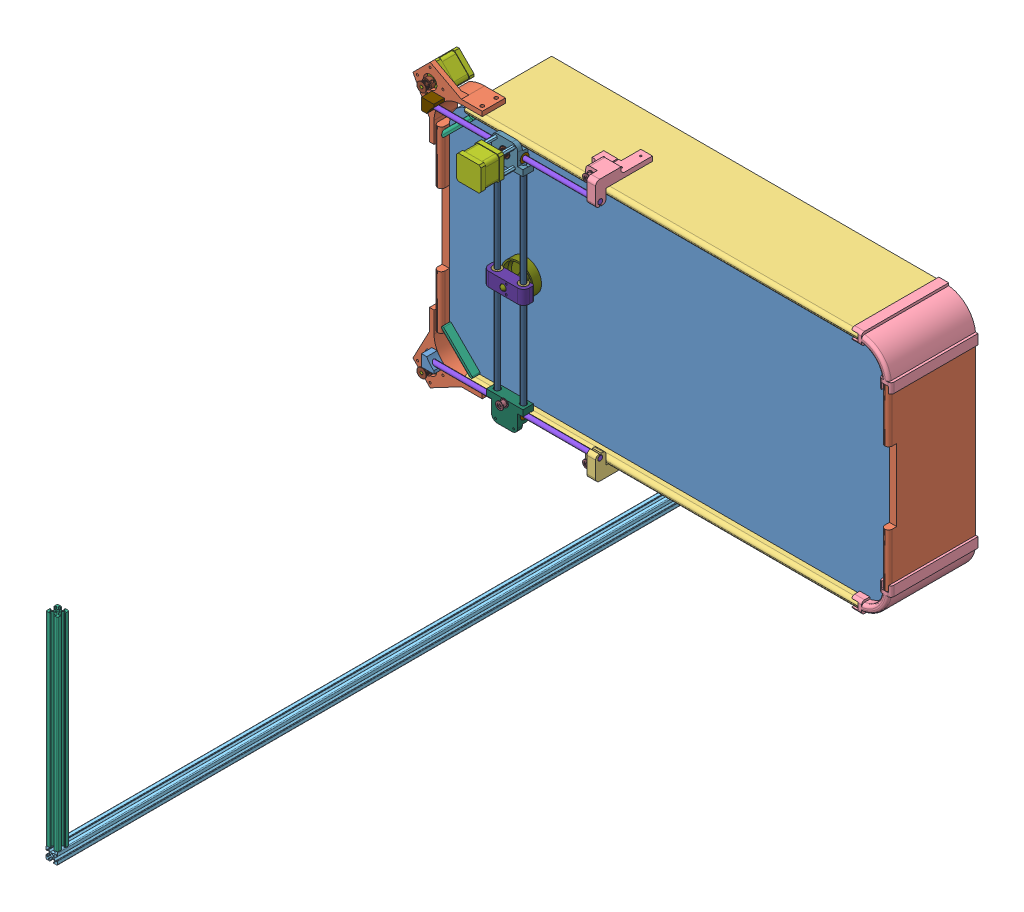
SolidWorks assembly 装配体, configuration 默认. Lengths in mm.
Overall size (823.44 485.88 1200).
44 component instances, 24 part files, 78 mates.
Components (placement in the parent):
- 球桌装配体-1: 球桌装配体 [默认] at (-24.8276 -49.5727 84.8566) size (787 421 150.29)
  - 桌面-1: 桌面 [默认] at (-446.8108 -166.0429 753) size (758 388 10)
  - 前后侧边-1: 前后侧边 [默认] at (-459.3108 -126.0429 627) x (0 1 0) z (1 0 0) size (308 150 12.5)
  - 左右侧边-1: 左右侧边 [默认] at (-406.8108 -166.0429 627) x (1 0 0) z (0 -1 0) size (678 150 12.5)
  - 左右侧边-2: 左右侧边 [默认] at (271.1892 221.9571 627) x (-1 0 0) z (0 1 0) size (678 150 12.5)
  - 前后侧边-2: 前后侧边 [默认] at (311.1892 -126.0429 627) x (0 1 0) z (1 0 0) size (308 150 12.5)
  - 倒角-1: 倒角 [默认] at (271.1892 -126.0429 777) x (1 0 0) z (0 0 -1) size (67.5 67.5 150.29)
  - 倒角-2: 倒角 [默认] at (271.1892 181.9571 777) x (0 1 0) z (0 0 -1) size (67.5 67.5 150.29)
- 摄像头支架装配体-1: 摄像头支架装配体 [默认] at (-93.6742 -242.7465 2511.8566) x (0 -1 0) z (0 0 -1) size (370 20 1200)
  - 2020型材-1: 2020型材 [默认<按加工>] at (-14.6309 -11.0359 600) size (20 20 1200)
  - 2020型材-2-1: 2020型材-2 [默认<按加工>] at (-364.6309 -11.0359 620) x (0 0 -1) z (1 0 0) size (20 20 350)
- 42步进-1: 42步进 [默认] at (-490.8785 191.6245 813.8566) x (-0.707107 -0.707107 0) z (0 0 1) size (42 42 63)
- 42步进-2: 42步进 [默认] at (-490.8785 -234.8557 813.8566) x (-0.707107 -0.707107 0) z (0 0 1) size (42 42 63)
- 300mm光轴-1: 300mm光轴 [默认] at (-487.8785 169.7044 871.8566) x (0 0.289314 0.957234) z (1 0 0) size (8 8 300)
- LM8UU直线轴承-45mm-1: LM8UU直线轴承-45mm [默认] at (-318.1095 169.7044 871.8566) x (0 0.333036 -0.942914) z (-1 0 0) size (15 15 45)
- 300mm光轴-2: 300mm光轴 [默认] at (-487.8785 -212.9356 871.8566) x (0 -0.484827 -0.87461) z (1 0 0) size (8 8 300)
- LM8UU直线轴承-45mm-2: LM8UU直线轴承-45mm [默认] at (-318.1095 -212.9356 871.8566) x (0 -0.829407 0.558645) z (-1 0 0) size (15 15 45)
- 450mm光轴-1: 450mm光轴 [默认] at (-363.1095 -199.2956 873.8566) x (-0.123162 0 0.992387) z (0 1 0) size (8 8 362)
- 450mm光轴-2: 450mm光轴 [默认] at (-318.1095 -199.2956 873.8566) x (-0.998234 0 0.059405) z (0 1 0) size (8 8 362)
- GT2同步轮内孔5-1: GT2同步轮内孔5 [默认] at (-490.8785 191.6245 860.8566) x (0.74409 0.66808 0) z (0 0 1) size (16 16 16)
- LM8UU直线轴承-24mm-1: LM8UU直线轴承-24mm [默认] at (-318.1095 -15.6742 873.8566) x (1 0 0) z (0 -1 0) size (15 15 24)
- LM8UU直线轴承-24mm-2: LM8UU直线轴承-24mm [默认] at (-363.1095 -15.6742 873.8566) x (1 0 0) z (0 -1 0) size (15 15 24)
- 惰轮（小）-1: 惰轮（小） [默认] at (-212.9285 191.6644 862.8566) size (13 13 9)
- Y轴滑块-左-1: Y轴滑块-左 [默认] at (-372.1095 182.2044 865.8566) x (1 0 0) z (0 -1 0) size (63 18 42)
- GT2同步轮内孔5-2: GT2同步轮内孔5 [默认] at (-490.8785 -234.8557 860.8566) x (0.265927 0.963993 0) z (0 0 1) size (16 16 16)
- Y轴滑块-右-1: Y轴滑块-右 [默认] at (-309.1095 -225.4356 865.8566) x (-1 0 0) z (0 1 0) size (63 18 42)
- 42步进-3: 42步进 [默认] at (-340.6095 172.9544 945.8566) x (0 1 0) z (0 0 -1) size (42 42 63)
- GT2同步轮内孔5-3: GT2同步轮内孔5 [默认] at (-340.6095 172.9544 898.8566) x (-0.6149 0.788605 0) z (0 0 -1) size (16 16 16)
- 惰轮（小）-2: 惰轮（小） [默认] at (-340.6095 -200.6856 884.8566) size (13 13 9)
- 打击器-2: 打击器 [默认] at (-340.6095 -27.6742 847.8566) x (0.889569 -0.456801 0) z (0 0 1) size (55 55 42)
- X轴滑块-3: X轴滑块 [默认] at (-375.6095 -39.6742 886.3566) x (1 0 0) z (0 1 0) size (70 19 24)
- 惰轮（小）-3: 惰轮（小） [默认] at (-212.9285 -234.8956 862.8566) x (0.977583 -0.210549 0) z (0 0 1) size (13 13 9)
- Y轴下端-1: Y轴下端 [默认] at (-487.8785 179.7044 861.8566) x (0 -1 0) z (0 0 1) size (20 29.29 18)
- Y轴下端-右-1: Y轴下端-右 [默认] at (-487.8785 -222.9356 879.8566) x (0 1 0) z (0 0 -1) size (20 29.29 18)
- 步进电机固定架-2: 步进电机固定架 [默认] at (-484.1384 184.8844 861.8566) x (1 0 0) z (0 0 -1) size (119.44 119.44 40)
- 步进电机固定架-3: 步进电机固定架 [默认] at (-484.1384 -228.1156 861.8566) x (0 1 0) z (0 0 -1) size (119.44 119.44 40)
- Y轴顶端固定件-右-2: Y轴顶端固定件-右 [默认] at (-202.8785 -236.1156 835.8566) x (0 1 0) z (1 0 0) size (40.92 98 50)
- Y轴顶端固定件-左-1: Y轴顶端固定件-左 [默认] at (-187.8785 192.8844 781.8566) x (0 -1 0) z (-1 0 0) size (40.92 98 50)
- 铜柱-1: 铜柱 [默认] at (-325.1095 188.4544 883.8566) size (6.35 5.5 27)
- 铜柱-2: 铜柱 [默认] at (-356.1095 188.4544 883.8566) x (0.90663 -0.421927 0) z (0 0 1) size (6.35 5.5 27)
- 铜柱-3: 铜柱 [默认] at (-325.1095 157.4544 883.8566) size (6.35 5.5 27)
- 铜柱-4: 铜柱 [默认] at (-356.1095 157.4544 883.8566) size (6.35 5.5 27)
- 机器人侧角件-1: 机器人侧角件 [默认] at (-471.6384 116.4902 847.8566) x (-1 0 0) z (0 0 1) size (53.07 53.07 13.51)
- 机器人侧角件-2: 机器人侧角件 [默认] at (-415.7442 -215.6156 847.8566) x (0 -1 0) z (0 0 1) size (53.07 53.07 13.51)
Mates (geometry in assembly coordinates):
- 重合2: coincident anti-aligned: plane of 球桌装配体-1/左右侧边-1 through (-431.6384 -228.1156 711.8566) normal (0 -1 0); plane of 摄像头支架装配体-1/2020型材-1 through (-82.6384 -228.1156 711.8566) normal (0 1 0)
- 重合3: coincident aligned: plane of 球桌装配体-1/左右侧边-1 through (-431.6384 -228.1156 711.8566) normal (0 0 -1); plane of 摄像头支架装配体-1/2020型材-1 through (-82.6384 -228.1156 711.8566) normal (0 0 -1)
- 距离1: distance = 381.5 mm aligned: plane of 摄像头支架装配体-1/2020型材-1 through (-82.6384 -228.1156 711.8566) normal (1 0 0); plane of 球桌装配体-1/前后侧边-2 through (298.8616 -175.6156 711.8566) normal (1 0 0)
- 同心6: concentric anti-aligned: cylinder of 300mm光轴-1 through (-187.8785 169.7044 871.8566) axis (-1 0 0) radius 4; cylinder of LM8UU直线轴承-45mm-1 through (-363.1095 169.7044 871.8566) axis (1 0 0) radius 4
- 同心11: concentric anti-aligned: cylinder of 300mm光轴-2 through (-187.8785 -212.9356 871.8566) axis (-1 0 0) radius 4; cylinder of LM8UU直线轴承-45mm-2 through (-363.1095 -212.9356 871.8566) axis (1 0 0) radius 4
- 同心19: concentric anti-aligned: cylinder of 42步进-1 through (-490.8785 191.6245 876.8566) axis (0 0 -1) radius 2.5; cylinder of GT2同步轮内孔5-1 through (-490.8785 191.6245 855.8566) axis (0 0 1) radius 2.5
- 重合28: coincident aligned: plane of 42步进-1 through (-490.8764 195.2003 876.8566) normal (0 0 1); plane of GT2同步轮内孔5-1 through (-490.8785 191.6245 876.8566) normal (0 0 1)
- 同心28: concentric anti-aligned: cylinder of 450mm光轴-2 through (-318.1095 162.7044 873.8566) axis (0 -1 0) radius 4; cylinder of LM8UU直线轴承-24mm-1 through (-318.1095 -39.6742 873.8566) axis (0 1 0) radius 4
- 同心29: concentric anti-aligned: cylinder of 450mm光轴-1 through (-363.1095 162.7044 873.8566) axis (0 -1 0) radius 4; cylinder of LM8UU直线轴承-24mm-2 through (-363.1095 -39.6742 873.8566) axis (0 1 0) radius 4
- 重合32: coincident aligned: plane of LM8UU直线轴承-24mm-1 through (-318.1095 -15.6742 873.8566) normal (0 1 0); plane of LM8UU直线轴承-24mm-2 through (-363.1095 -15.6742 873.8566) normal (0 1 0)
- 同心36: concentric anti-aligned: cylinder of LM8UU直线轴承-45mm-1 through (-363.1095 169.7044 871.8566) axis (1 0 0) radius 7.5; cylinder of Y轴滑块-左-1 through (-303.1095 169.7044 871.8566) axis (-1 0 0) radius 7.65
- 同心38: concentric aligned: cylinder of 450mm光轴-2 through (-318.1095 162.7044 873.8566) axis (0 -1 0) radius 4; cylinder of Y轴滑块-左-1 through (-318.1095 168.2044 873.8566) axis (0 -1 0) radius 4.2
- 重合37: coincident aligned: plane of LM8UU直线轴承-45mm-1 through (-363.1095 169.7044 871.8566) normal (-1 0 0); plane of Y轴滑块-左-1 through (-363.1095 162.7044 848.8566) normal (-1 0 0)
- 重合38: coincident aligned: plane of 42步进-2 through (-490.8764 -231.2799 876.8566) normal (0 0 1); plane of GT2同步轮内孔5-2 through (-490.8785 -234.8557 876.8566) normal (0 0 1)
- 同心39: concentric anti-aligned: cylinder of 42步进-2 through (-490.8785 -234.8557 876.8566) axis (0 0 -1) radius 2.5; cylinder of GT2同步轮内孔5-2 through (-490.8785 -234.8557 855.8566) axis (0 0 1) radius 2.5
- 同心40: concentric aligned: cylinder of LM8UU直线轴承-45mm-2 through (-363.1095 -212.9356 871.8566) axis (1 0 0) radius 7.5; cylinder of Y轴滑块-右-1 through (-378.1095 -212.9356 871.8566) axis (1 0 0) radius 7.65
- 同心42: concentric anti-aligned: cylinder of 450mm光轴-1 through (-363.1095 162.7044 873.8566) axis (0 -1 0) radius 4; cylinder of Y轴滑块-右-1 through (-363.1095 -211.4356 873.8566) axis (0 1 0) radius 4.2
- 同心43: concentric aligned: cylinder of 450mm光轴-1 through (-363.1095 162.7044 873.8566) axis (0 -1 0) radius 4; cylinder of Y轴滑块-左-1 through (-363.1095 168.2044 873.8566) axis (0 -1 0) radius 4.2
- 同心46: concentric aligned: cylinder of Y轴滑块-左-1 through (-340.6095 172.9544 875.8566) axis (0 0 1) radius 9; cylinder of 42步进-3 through (-340.6095 172.9544 903.8566) axis (0 0 1) radius 11
- 平行4: parallel aligned: plane of Y轴滑块-左-1 through (-372.1095 194.2044 865.8566) normal (0 1 0); plane of 42步进-3 through (-322.6095 193.9544 913.8566) normal (0 1 0)
- 重合40: coincident aligned: plane of 42步进-3 through (-343.1365 170.4244 882.8566) normal (0 0 -1); plane of GT2同步轮内孔5-3 through (-340.6095 172.9544 882.8566) normal (0 0 -1)
- 同心47: concentric anti-aligned: cylinder of 42步进-3 through (-340.6095 172.9544 882.8566) axis (0 0 1) radius 2.5; cylinder of GT2同步轮内孔5-3 through (-340.6095 172.9544 903.8566) axis (0 0 -1) radius 2.5
- 重合41: coincident aligned: plane of Y轴滑块-左-1 through (-372.1095 152.2044 883.8566) normal (0 0 1); plane of GT2同步轮内孔5-3 through (-340.6095 172.9544 883.8566) normal (0 0 1)
- 重合42: coincident anti-aligned: plane of Y轴滑块-右-1 through (-309.1095 -195.4356 883.8566) normal (0 0 1); plane of 惰轮（小）-2 through (-340.6095 -200.6856 883.8566) normal (0 0 -1)
- 同心48: concentric anti-aligned: cylinder of Y轴滑块-右-1 through (-340.6095 -200.6856 863.8566) axis (0 0 1) radius 1.65; cylinder of 惰轮（小）-2 through (-340.6095 -200.6856 895.8566) axis (0 0 -1) radius 1.5
- 重合43: coincident anti-aligned: plane of 球桌装配体-1/桌面-1 through (-471.6384 -215.6156 847.8566) normal (0 0 1); plane of 打击器-2 through (-340.6095 -27.6742 847.8566) normal (0 0 -1)
- 同心50: concentric aligned: cylinder of LM8UU直线轴承-24mm-1 through (-318.1095 -39.6742 873.8566) axis (0 1 0) radius 7.5; cylinder of X轴滑块-3 through (-318.1095 -39.6742 873.8566) axis (0 1 0) radius 7.65
- 同心51: concentric aligned: cylinder of LM8UU直线轴承-24mm-2 through (-363.1095 -39.6742 873.8566) axis (0 1 0) radius 7.5; cylinder of X轴滑块-3 through (-363.1095 -39.6742 873.8566) axis (0 1 0) radius 7.65
- 重合44: coincident aligned: plane of LM8UU直线轴承-24mm-2 through (-363.1095 -39.6742 873.8566) normal (0 -1 0); plane of X轴滑块-3 through (-375.6095 -39.6742 886.3566) normal (0 -1 0)
- 同心52: concentric anti-aligned: cylinder of 打击器-2 through (-340.6095 -27.6742 889.8566) axis (0 0 -1) radius 5; cylinder of X轴滑块-3 through (-340.6095 -27.6742 862.3566) axis (0 0 1) radius 5.3
- 重合45: coincident aligned: plane of LM8UU直线轴承-45mm-2 through (-363.1095 -212.9356 871.8566) normal (-1 0 0); plane of Y轴滑块-右-1 through (-363.1095 -225.4356 848.8566) normal (-1 0 0)
- 同心57: concentric aligned: cylinder of 300mm光轴-1 through (-187.8785 169.7044 871.8566) axis (-1 0 0) radius 4; cylinder of Y轴下端-1 through (-459.8785 169.7044 871.8566) axis (-1 0 0) radius 4.2
- 同心60: concentric aligned: cylinder of 300mm光轴-2 through (-187.8785 -212.9356 871.8566) axis (-1 0 0) radius 4; cylinder of Y轴下端-右-1 through (-459.8785 -212.9356 871.8566) axis (-1 0 0) radius 4.2
- 重合68: coincident aligned: plane of 300mm光轴-1 through (-487.8785 169.7044 871.8566) normal (-1 0 0); plane of Y轴下端-1 through (-487.8785 179.7044 879.8566) normal (-1 0 0)
- 重合69: coincident aligned: plane of 300mm光轴-2 through (-487.8785 -212.9356 871.8566) normal (-1 0 0); plane of Y轴下端-右-1 through (-487.8785 -222.9356 861.8566) normal (-1 0 0)
- 重合70: coincident aligned: plane of 球桌装配体-1/倒角-2 through (246.3616 132.3844 861.8566) normal (0 0 1); plane of 步进电机固定架-2 through (-437.1384 137.8844 861.8566) normal (0 0 1)
- 重合71: coincident anti-aligned: plane of 球桌装配体-1/左右侧边-2 through (246.3616 184.8844 711.8566) normal (0 1 0); plane of 步进电机固定架-2 through (-437.1384 184.8844 821.8566) normal (0 -1 0)
- 重合72: coincident anti-aligned: plane of 球桌装配体-1/前后侧边-1 through (-484.1384 -175.6156 711.8566) normal (-1 0 0); plane of 步进电机固定架-2 through (-484.1384 137.8844 821.8566) normal (1 0 0)
- 重合73: coincident anti-aligned: plane of 42步进-1 through (-490.8785 221.323 853.8566) normal (0 0 1); plane of 步进电机固定架-2 through (-437.1384 137.8844 853.8566) normal (0 0 -1)
- 同心61: concentric anti-aligned: cylinder of 42步进-1 through (-490.8785 191.6245 855.8566) axis (0 0 -1) radius 11; cylinder of 步进电机固定架-2 through (-490.8785 191.6245 853.8566) axis (0 0 1) radius 11.5
- 平行5: parallel aligned: plane of 42步进-1 through (-492.9998 219.2017 845.8566) normal (-0.707107 0.707107 0); plane of 步进电机固定架-2 through (-490.8785 221.323 853.8566) normal (-0.707107 0.707107 0)
- 重合74: coincident anti-aligned: plane of Y轴下端-1 through (-437.1385 137.8844 861.8566) normal (0 0 -1); plane of 步进电机固定架-2 through (-437.1384 137.8844 861.8566) normal (0 0 1)
- 同心62: concentric aligned: cylinder of Y轴下端-1 through (-490.8785 169.7044 856.8566) axis (0 0 1) radius 1.6; cylinder of 步进电机固定架-2 through (-490.8785 169.7042 853.8566) axis (0 0 1) radius 1.8
- 重合79: coincident aligned: plane of 步进电机固定架-2 through (-437.1384 137.8844 861.8566) normal (0 0 1); plane of 步进电机固定架-3 through (-437.1384 -181.1156 861.8566) normal (0 0 1)
- 重合80: coincident anti-aligned: plane of 球桌装配体-1/左右侧边-1 through (-431.6384 -228.1156 711.8566) normal (0 -1 0); plane of 步进电机固定架-3 through (-437.1384 -228.1156 821.8566) normal (0 1 0)
- 重合81: coincident anti-aligned: plane of 球桌装配体-1/前后侧边-1 through (-484.1384 -175.6156 711.8566) normal (-1 0 0); plane of 步进电机固定架-3 through (-484.1384 -181.1156 821.8566) normal (1 0 0)
- 重合82: coincident anti-aligned: plane of 42步进-2 through (-490.8785 -205.1573 853.8566) normal (0 0 1); plane of 步进电机固定架-3 through (-437.1384 -181.1156 853.8566) normal (0 0 -1)
- 同心65: concentric anti-aligned: cylinder of 42步进-2 through (-490.8785 -234.8557 855.8566) axis (0 0 -1) radius 11; cylinder of 步进电机固定架-3 through (-490.8785 -234.8557 853.8566) axis (0 0 1) radius 11.5
- 平行8: parallel aligned: plane of 42步进-2 through (-492.9998 -262.4329 845.8566) normal (-0.707107 -0.707107 0); plane of 步进电机固定架-3 through (-520.577 -234.8557 853.8566) normal (-0.707107 -0.707107 0)
- 同心66: concentric anti-aligned: cylinder of 450mm光轴-2 through (-318.1095 162.7044 873.8566) axis (0 -1 0) radius 4; cylinder of Y轴滑块-右-1 through (-318.1095 -211.4356 873.8566) axis (0 1 0) radius 4.2
- 重合84: coincident anti-aligned: plane of Y轴下端-右-1 through (-437.1385 -181.1156 861.8566) normal (0 0 -1); plane of 步进电机固定架-3 through (-437.1384 -181.1156 861.8566) normal (0 0 1)
- 同心67: concentric aligned: cylinder of Y轴下端-右-1 through (-490.8785 -212.9356 856.8566) axis (0 0 1) radius 1.6; cylinder of 步进电机固定架-3 through (-490.8785 -212.9354 853.8566) axis (0 0 1) radius 1.8
- 同心68: concentric aligned: cylinder of 300mm光轴-2 through (-187.8785 -212.9356 871.8566) axis (-1 0 0) radius 4; cylinder of Y轴顶端固定件-右-2 through (-187.8785 -212.9356 871.8566) axis (-1 0 0) radius 4.2
- 重合85: coincident anti-aligned: plane of 球桌装配体-1/左右侧边-1 through (-431.6384 -228.1156 711.8566) normal (0 -1 0); plane of Y轴顶端固定件-右-2 through (-187.8785 -228.1156 781.8566) normal (0 1 0)
- 重合86: coincident aligned: plane of 300mm光轴-2 through (-187.8785 -212.9356 871.8566) normal (1 0 0); plane of Y轴顶端固定件-右-2 through (-187.8785 -236.1156 835.8566) normal (1 0 0)
- 重合87: coincident anti-aligned: plane of 惰轮（小）-3 through (-212.9285 -234.8956 861.8566) normal (0 0 -1); plane of Y轴顶端固定件-右-2 through (-222.8785 -228.1156 861.8566) normal (0 0 1)
- 同心69: concentric anti-aligned: cylinder of 惰轮（小）-3 through (-212.9285 -234.8956 873.8566) axis (0 0 -1) radius 1.5; cylinder of Y轴顶端固定件-右-2 through (-212.9285 -234.8956 768.8566) axis (0 0 1) radius 1.6
- 同心70: concentric aligned: cylinder of 300mm光轴-1 through (-187.8785 169.7044 871.8566) axis (-1 0 0) radius 4; cylinder of Y轴顶端固定件-左-1 through (-172.8785 169.7044 871.8566) axis (-1 0 0) radius 4.2
- 重合88: coincident anti-aligned: plane of 球桌装配体-1/左右侧边-2 through (246.3616 184.8844 711.8566) normal (0 1 0); plane of Y轴顶端固定件-左-1 through (-202.8785 184.8844 781.8566) normal (0 -1 0)
- 重合89: coincident aligned: plane of 300mm光轴-1 through (-187.8785 169.7044 871.8566) normal (1 0 0); plane of Y轴顶端固定件-左-1 through (-187.8785 192.8844 781.8566) normal (1 0 0)
- 重合90: coincident anti-aligned: plane of 惰轮（小）-1 through (-212.9285 191.6644 861.8566) normal (0 0 -1); plane of Y轴顶端固定件-左-1 through (-222.8785 184.8844 861.8566) normal (0 0 1)
- 同心71: concentric anti-aligned: cylinder of 惰轮（小）-1 through (-212.9285 191.6644 873.8566) axis (0 0 -1) radius 1.5; cylinder of Y轴顶端固定件-左-1 through (-212.9285 191.6644 682.8566) axis (0 0 1) radius 1.6
- 重合95: coincident aligned: plane of 450mm光轴-2 through (-318.1095 162.7044 873.8566) normal (0 1 0); plane of Y轴滑块-左-1 through (-318.1095 162.7044 848.8566) normal (0 1 0)
- 重合96: coincident aligned: plane of 450mm光轴-1 through (-363.1095 162.7044 873.8566) normal (0 1 0); plane of Y轴滑块-左-1 through (-372.1095 162.7044 848.8566) normal (0 1 0)
- 同心72: concentric aligned: cylinder of 42步进-3 through (-325.1095 188.4544 915.8566) axis (0 0 -1) radius 1.5; cylinder of 铜柱-1 through (-325.1095 188.4544 910.8566) axis (0 0 -1) radius 1.5
- 重合97: coincident anti-aligned: plane of 42步进-3 through (-361.6095 151.9544 905.8566) normal (0 0 -1); plane of 铜柱-1 through (-325.1095 188.4544 905.8566) normal (0 0 1)
- 同心73: concentric aligned: cylinder of 42步进-3 through (-356.1095 188.4544 915.8566) axis (0 0 -1) radius 1.5; cylinder of 铜柱-2 through (-356.1095 188.4544 910.8566) axis (0 0 -1) radius 1.5
- 重合98: coincident anti-aligned: plane of 42步进-3 through (-361.6095 151.9544 905.8566) normal (0 0 -1); plane of 铜柱-2 through (-356.1095 188.4544 905.8566) normal (0 0 1)
- 重合99: coincident anti-aligned: plane of 42步进-3 through (-361.6095 151.9544 905.8566) normal (0 0 -1); plane of 铜柱-4 through (-356.1095 157.4544 905.8566) normal (0 0 1)
- 同心75: concentric aligned: cylinder of 42步进-3 through (-356.1095 157.4544 915.8566) axis (0 0 -1) radius 1.5; cylinder of 铜柱-4 through (-356.1095 157.4544 910.8566) axis (0 0 -1) radius 1.5
- 重合100: coincident anti-aligned: plane of 42步进-3 through (-361.6095 151.9544 905.8566) normal (0 0 -1); plane of 铜柱-3 through (-325.1095 157.4544 905.8566) normal (0 0 1)
- 同心76: concentric aligned: cylinder of 42步进-3 through (-325.1095 157.4544 915.8566) axis (0 0 -1) radius 1.5; cylinder of 铜柱-3 through (-325.1095 157.4544 910.8566) axis (0 0 -1) radius 1.5
- 重合104: coincident: plane of 球桌装配体-1/桌面-1 through (-471.6384 -215.6156 847.8566) normal (0 0 1); plane of 机器人侧角件-1 through (-446.6435 116.4902 847.8566) normal (0 0 -1)
- 重合105: coincident: plane of 球桌装配体-1/左右侧边-2 through (246.3616 172.3844 711.8566) normal (0 -1 0); plane of 机器人侧角件-1 through (-402.4493 172.3844 861.3566) normal (0 1 0)
- 重合106: coincident anti-aligned: plane of 球桌装配体-1/前后侧边-1 through (-471.6384 -175.6156 711.8566) normal (1 0 0); plane of 机器人侧角件-1 through (-471.6384 116.4902 861.3566) normal (-1 0 0)
- 重合107: coincident: plane of 球桌装配体-1/桌面-1 through (-471.6384 -215.6156 847.8566) normal (0 0 1); plane of 机器人侧角件-2 through (-415.7442 -35.2243 847.8566) normal (0 0 -1)
- 重合108: coincident: plane of 球桌装配体-1/前后侧边-1 through (-471.6384 -175.6156 711.8566) normal (1 0 0); plane of 机器人侧角件-2 through (-471.6384 8.9699 861.3566) normal (-1 0 0)
- 重合109: coincident anti-aligned: plane of 球桌装配体-1/左右侧边-1 through (-431.6384 -215.6156 711.8566) normal (0 1 0); plane of 机器人侧角件-2 through (-415.7442 -215.6156 861.3566) normal (0 -1 0)
